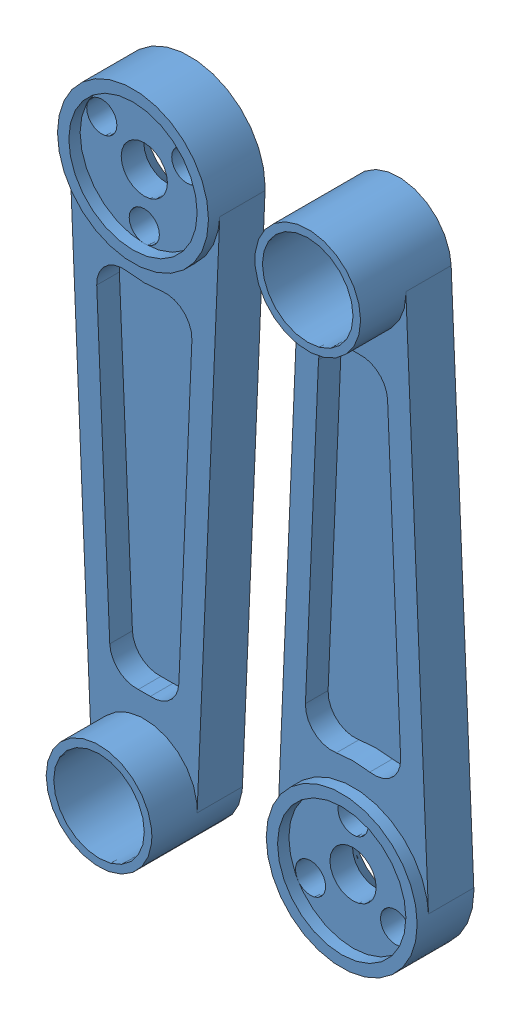
SolidWorks assembly cam5, configuration Default. Lengths in mm.
Overall size (49 152 12.5).
2 component instances, 1 part files, 4 mates.
Components (placement in the parent):
- Link 1-1: Link 1 [Default] at (9.1732 79.54 37.5298) size (20 87 12)
- Link 1-2: Link 1 [Default] at (36.816 12.54 37.5298) x (-1 0 0) z (0 0 1) size (20 87 12)
Mates (geometry in assembly coordinates):
- Coincident1: coincident aligned: plane of Link 1-1 through (9.1732 79.54 37.5298) normal (0 0 -1); plane of Link 1-2 through (36.816 12.54 37.5298) normal (0 0 -1)
- Parallel1: parallel anti-aligned: plane of Link 1-1 through (19.164 79.1114 43.5298) normal (0.999081 -0.042857 0); plane of Link 1-2 through (26.8252 12.9686 43.5298) normal (-0.999081 0.042857 0)
- Tangent1: tangent anti-aligned: cylinder of Link 1-1 through (9.1732 9.54 43.5298) axis (0 0 -1) radius 7; plane of assembly through (0 2.54 0) normal (0 1 0)
- Tangent2: tangent anti-aligned: cylinder of Link 1-2 through (36.816 12.54 43.5298) axis (0 0 -1) radius 10; plane of assembly through (0 2.54 0) normal (0 1 0)
